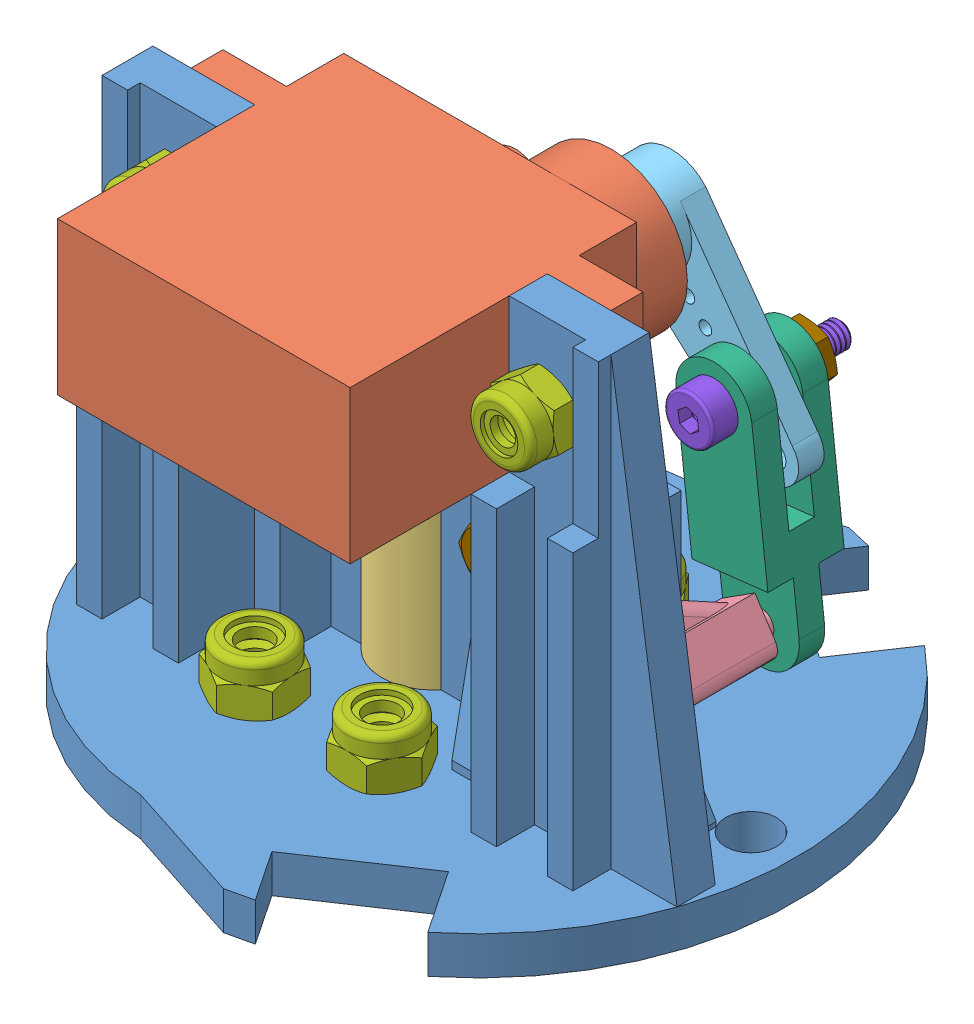
SolidWorks assembly Rückseite, configuration Standard. Lengths in mm.
Overall size (50 44.39 49.14).
19 component instances, 10 part files, 39 mates.
Components (placement in the parent):
- Backside-1: Backside [Standard] at (-0.7502 -6.4244 50) size (50 38 49.14)
- servo-1: servo [Standard] at (-9.7502 31.5756 70.5) x (1 0 0) z (0 1 0) size (33 29.25 12)
- Drücker-1: Drücker [Standard] at (-2.5879 16.1812 78.2478) x (1 0 0) z (0 0 -1) size (8 29 8)
- Hebel-1: Hebel [Standard] at (9.2498 10.5756 51) x (0.955006 -0.296586 0) z (0 0 -1) size (29.78 9.71 13)
- Servo-Arm-1: Servo-Arm [Standard] at (7.2498 25.5756 39.25) x (0.666417 -0.745579 0) z (-0.745579 -0.666417 0) size (20.6 4.3 7.2)
- Hebel2-1: Hebel2 [Standard] at (16.3026 2.4734 39.25) x (-0.114811 0.993387 0) z (0.993387 0.114811 0) size (21 6 6)
- User Library-Mutter DIN-985_-1: User Library-Mutter DIN-985_ [Mutter DIN-985 M3-A2] at (-4.7502 -3.4244 60) x (0 1 0) z (-0.455135 0 0.890422) size (4 6.35 5.5)
- User Library-Mutter DIN-985_-2: User Library-Mutter DIN-985_ [Mutter DIN-985 M3-A2] at (5.2498 -3.4244 60) x (0 1 0) z (-0.871788 0 0.489884) size (4 6.35 5.5)
- User Library-Mutter DIN-985_-3: User Library-Mutter DIN-985_ [Mutter DIN-985 M3-A2] at (5.2498 -3.4244 40) x (0 1 0) z (-0.77566 0 0.631152) size (4 6.35 5.5)
- User Library-Mutter DIN-985_-4: User Library-Mutter DIN-985_ [Mutter DIN-985 M3-A2] at (-4.7502 -3.4244 40) x (0 1 0) z (-0.229708 0 0.97326) size (4 6.35 5.5)
- socket head cap screw 4762_din-1: socket head cap screw 4762_din [ISO 4762 M2 x 10 --- 10S] at (9.2498 10.5756 43.8) x (0 0 1) z (0.035285 -0.999377 0) size (12 3.8 3.8)
- socket head cap screw 4762_din-2: socket head cap screw 4762_din [ISO 4762 M2 x 10 --- 10S] at (-0.7502 13.6812 55) x (0 0 -1) z (0.809309 -0.587383 0) size (12 3.8 3.8)
- socket head cap screw 4762_din-3: socket head cap screw 4762_din [ISO 4762 M2 x 10 --- 10S] at (14.5804 17.3743 45.25) x (0 0 -1) z (-0.62056 0.784159 0) size (12 3.8 3.8)
- nut__style_1__m2x0_4__ansi_b18_2_4_1m-1: nut__style_1__m2x0_4__ansi_b18_2_4_1m [Default] at (-0.7502 13.6812 47) x (0.83114 0.556064 0) z (0 0 -1) size (4.62 4 1.6)
- nut__style_1__m2x0_4__ansi_b18_2_4_1m-2: nut__style_1__m2x0_4__ansi_b18_2_4_1m [Default] at (14.5804 17.3743 35.65) x (0.980747 -0.195284 0) z (0 0 1) size (4.62 4 1.6)
- nut__style_1__m2x0_4__ansi_b18_2_4_1m-3: nut__style_1__m2x0_4__ansi_b18_2_4_1m [Default] at (9.2498 10.5756 54.2) x (0.532315 -0.846547 0) z (0 0 1) size (4.62 4 1.6)
- User Library-Mutter DIN-985_-5: User Library-Mutter DIN-985_ [Mutter DIN-985 M2,5-A2] at (-12.7502 25.5756 58) x (0 0 1) z (0.965495 0.260421 0) size (3.8 5.77 5)
- User Library-Mutter DIN-985_-6: User Library-Mutter DIN-985_ [Mutter DIN-985 M2,5-A2] at (16.2498 25.5756 58) x (0 0 1) z (-0.395566 -0.918438 0) size (3.8 5.77 5)
- oval head sheet metal screw_din-1: oval head sheet metal screw_din [Tapping screw DIN 7983-ST2.9x6.5-F-H-S] at (7.2498 25.5756 40.6565) x (0 0 1) z (-0.615967 -0.787772 0) size (7.15 5.82 5.82)
Mates (geometry in assembly coordinates):
- Konzentrisch1: concentric anti-aligned: cylinder of Drücker-1 through (-0.7502 -12.8188 50) axis (0 1 0) radius 4; cylinder of Backside-1 through (-0.7502 -3.4244 50) axis (0 -1 0) radius 4
- Konzentrisch2: concentric aligned: cylinder of Backside-1 through (9.2498 10.5756 57.5) axis (0 0 1) radius 1.15; cylinder of Hebel-1 through (9.2498 10.5756 49) axis (0 0 1) radius 1
- Deckungsgleich1: coincident anti-aligned: plane of Hebel-1 through (9.2498 10.5756 49) normal (0 0 -1); plane of Backside-1 through (6.7498 13.5756 49) normal (0 0 1)
- Parallel1: parallel anti-aligned: plane of Drücker-1 through (-5.7502 8.1812 51) normal (0 0 -1); plane of Hebel-1 through (9.2498 10.5756 51) normal (0 0 1)
- Langloch1: slot anti-aligned: cylinder of Drücker-1 through (-0.7502 13.6812 54) axis (0 0 -1) radius 1; plane of Hebel-1 through (9.5464 11.5306 49) normal (-0.296586 -0.955006 0); cylinder of Hebel-1 through (-6.0303 15.321 49) axis (0 0 1) radius 1
- Konzentrisch3: concentric anti-aligned: cylinder of servo-1 through (7.2498 25.5756 44) axis (0 0 1) radius 6; cylinder of Servo-Arm-1 through (7.2498 25.5756 43.55) axis (0 0 -1) radius 2.25
- Deckungsgleich6: coincident anti-aligned: plane of Backside-1 through (-9.7502 31.5756 58) normal (1 0 0); plane of servo-1 through (-9.7502 31.5756 48) normal (-1 0 0)
- Deckungsgleich7: coincident anti-aligned: plane of servo-1 through (18.2498 31.5756 55) normal (0 0 1); plane of Backside-1 through (-17.7502 19.5756 55) normal (0 0 -1)
- Deckungsgleich11: coincident aligned: plane of Backside-1 through (-0.7502 31.5756 50) normal (0 1 0); plane of servo-1 through (-9.7502 31.5756 48) normal (0 1 0)
- Deckungsgleich9: coincident anti-aligned: plane of Servo-Arm-1 through (7.2498 25.5756 39.25) normal (0 0 -1); plane of Hebel2-1 through (16.3026 2.4734 39.25) normal (0 0 1)
- Konzentrisch4: concentric anti-aligned: cylinder of Hebel-1 through (16.3026 2.4734 38) axis (0 0 1) radius 1; cylinder of Hebel2-1 through (16.3026 2.4734 41.25) axis (0 0 -1) radius 1
- Deckungsgleich12: coincident anti-aligned: plane of servo-1 through (7.2498 25.5756 41.25) normal (0 0 -1); plane of Servo-Arm-1 through (7.2498 25.5756 41.25) normal (0 0 1)
- Konzentrisch5: concentric aligned: cylinder of Servo-Arm-1 through (14.5804 17.3743 41.25) axis (0 0 -1) radius 0.5; cylinder of Hebel2-1 through (14.5804 17.3743 41.25) axis (0 0 -1) radius 1
- Deckungsgleich28: coincident anti-aligned: plane of Backside-1 through (-0.7502 -3.4244 50) normal (0 1 0); plane of User Library-Mutter DIN-985_-1 through (-7.1799 -3.4244 58.7581) normal (0 -1 0)
- Deckungsgleich29: coincident anti-aligned: plane of Backside-1 through (-0.7502 -3.4244 50) normal (0 1 0); plane of User Library-Mutter DIN-985_-2 through (3.9131 -3.4244 57.6211) normal (0 -1 0)
- Deckungsgleich31: coincident anti-aligned: plane of Backside-1 through (-0.7502 -3.4244 50) normal (0 1 0); plane of User Library-Mutter DIN-985_-3 through (3.5276 -3.4244 37.8834) normal (0 -1 0)
- Deckungsgleich30: coincident anti-aligned: plane of Backside-1 through (-0.7502 -3.4244 50) normal (0 1 0); plane of User Library-Mutter DIN-985_-4 through (-7.4059 -3.4244 39.3732) normal (0 -1 0)
- Deckungsgleich21: coincident anti-aligned: plane of Backside-1 through (9.2498 10.5756 45.8) normal (0 0 -1); plane of socket head cap screw 4762_din-1 through (7.351 10.5086 45.8) normal (0 0 1)
- Konzentrisch20: concentric anti-aligned: cylinder of Backside-1 through (9.2498 10.5756 57.5) axis (0 0 1) radius 1.15; cylinder of socket head cap screw 4762_din-1 through (9.2498 10.5756 12.05) axis (0 0 -1) radius 1
- Konzentrisch19: concentric anti-aligned: cylinder of Drücker-1 through (-0.7502 13.6812 54) axis (0 0 -1) radius 1; cylinder of socket head cap screw 4762_din-2 through (-0.7502 13.6812 86.75) axis (0 0 1) radius 1
- Deckungsgleich38: coincident anti-aligned: plane of Hebel2-1 through (16.3026 2.4734 43.25) normal (0 0 1); plane of socket head cap screw 4762_din-3 through (13.0905 16.1952 43.25) normal (0 0 -1)
- Konzentrisch38: concentric anti-aligned: cylinder of Hebel2-1 through (14.5804 17.3743 41.25) axis (0 0 -1) radius 1; cylinder of socket head cap screw 4762_din-3 through (14.5804 17.3743 77) axis (0 0 1) radius 1
- Deckungsgleich41: coincident anti-aligned: plane of Drücker-1 through (4.2498 8.1812 47) normal (0 0 -1); plane of nut__style_1__m2x0_4__ansi_b18_2_4_1m-1 through (1.1698 14.9657 47) normal (0 0 1)
- Konzentrisch49: concentric aligned: circle of socket head cap screw 4762_din-2; circle of nut__style_1__m2x0_4__ansi_b18_2_4_1m-1
- Deckungsgleich39: coincident anti-aligned: plane of Hebel2-1 through (16.3026 2.4734 37.25) normal (0 0 -1); plane of nut__style_1__m2x0_4__ansi_b18_2_4_1m-2 through (16.8459 16.9231 37.25) normal (0 0 1)
- Konzentrisch50: concentric anti-aligned: circle of socket head cap screw 4762_din-3; circle of nut__style_1__m2x0_4__ansi_b18_2_4_1m-2
- Deckungsgleich33: coincident anti-aligned: plane of Backside-1 through (9.2498 10.5756 54.2) normal (0 0 1); plane of nut__style_1__m2x0_4__ansi_b18_2_4_1m-3 through (10.4795 8.6201 54.2) normal (0 0 -1)
- Konzentrisch48: concentric aligned: circle of socket head cap screw 4762_din-1; circle of nut__style_1__m2x0_4__ansi_b18_2_4_1m-3
- Deckungsgleich36: coincident anti-aligned: plane of Backside-1 through (-11.7502 31.5756 58) normal (0 0 1); plane of User Library-Mutter DIN-985_-5 through (-12.1447 23.3307 58) normal (0 0 -1)
- Deckungsgleich37: coincident anti-aligned: plane of Backside-1 through (15.2498 31.5756 58) normal (0 0 1); plane of User Library-Mutter DIN-985_-6 through (14.1143 26.4954 58) normal (0 0 -1)
- Konzentrisch51: concentric aligned: circle of Backside-1; circle of User Library-Mutter DIN-985_-1
- Konzentrisch52: concentric aligned: circle of Backside-1; circle of User Library-Mutter DIN-985_-2
- Konzentrisch53: concentric aligned: circle of Backside-1; circle of User Library-Mutter DIN-985_-4
- Konzentrisch54: concentric aligned: circle of Backside-1; circle of User Library-Mutter DIN-985_-3
- Konzentrisch55: concentric aligned: circle of User Library-Mutter DIN-985_-5; cylinder of Backside-1 through (-12.7502 25.5756 41) axis (0 0 1) radius 1.25
- Konzentrisch56: concentric aligned: circle of User Library-Mutter DIN-985_-6; cylinder of Backside-1 through (16.2498 25.5756 41) axis (0 0 1) radius 1.25
- Deckungsgleich40: coincident anti-aligned: plane of Drücker-1 through (4.2498 8.1812 53) normal (0 0 1); plane of socket head cap screw 4762_din-2 through (0.3658 15.2189 53) normal (0 0 -1)
- Konzentrisch58: concentric anti-aligned: circle of Servo-Arm-1; circle of oval head sheet metal screw_din-1
- Tangential8: tangent: plane of Servo-Arm-1 through (7.2498 25.5756 39.25) normal (0 0 -1); circle of oval head sheet metal screw_din-1
